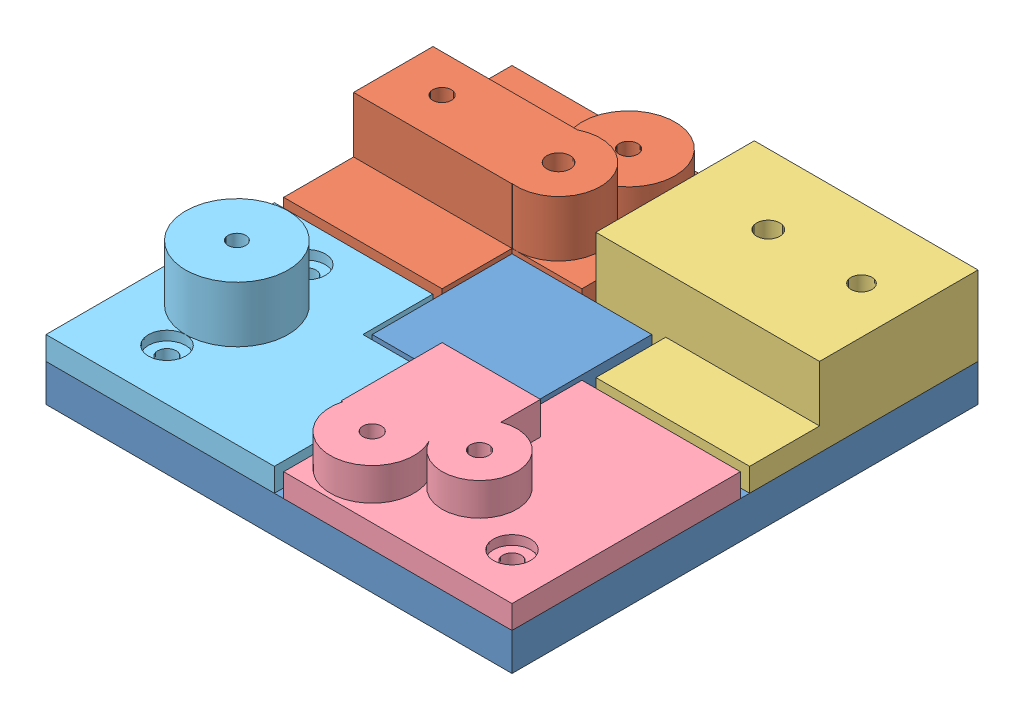
SolidWorks assembly model, configuration Default. Lengths in mm.
Overall size (100 25 100).
5 component instances, 5 part files, 12 mates.
Components (placement in the parent):
- model_1-1: model_1 [Default] at (3.4761 37.87 104.3471) size (100 13 100)
- model_2-1: model_2 [Default] at (3.4761 45.87 53.3471) size (49 17 49)
- model_3-1: model_3 [Default] at (55.4761 45.87 53.3471) size (48 17 49)
- model_4-1: model_4 [Default] at (54.4761 45.87 104.3471) size (49 12 49)
- model_5-1: model_5 [Default] at (3.4761 45.87 104.3471) size (49 17 49)
Mates (geometry in assembly coordinates):
- Coincident1: coincident: plane of model_1-1 through (3.4761 45.87 104.3471) normal (0 1 0); plane of model_2-1 through (3.4761 45.87 53.3471) normal (0 -1 0)
- Coincident2: coincident: plane of model_1-1 through (3.4761 45.87 4.3471) normal (0 0 -1); plane of model_2-1 through (3.4761 50.87 4.3471) normal (0 0 -1)
- Coincident3: coincident aligned: plane of model_1-1 through (3.4761 45.87 104.3471) normal (-1 0 0); plane of model_2-1 through (3.4761 50.87 53.3471) normal (-1 0 0)
- Coincident4: coincident: plane of model_1-1 through (3.4761 45.87 104.3471) normal (0 1 0); plane of model_3-1 through (55.4761 45.87 53.3471) normal (0 -1 0)
- Coincident5: coincident: plane of model_1-1 through (103.4761 45.87 104.3471) normal (1 0 0); plane of model_3-1 through (103.4761 50.87 53.3471) normal (1 0 0)
- Coincident6: coincident aligned: plane of model_1-1 through (3.4761 45.87 4.3471) normal (0 0 -1); plane of model_3-1 through (55.4761 50.87 4.3471) normal (0 0 -1)
- Coincident7: coincident: plane of model_1-1 through (3.4761 45.87 104.3471) normal (0 1 0); plane of model_4-1 through (54.4761 45.87 104.3471) normal (0 -1 0)
- Coincident8: coincident: plane of model_1-1 through (103.4761 45.87 104.3471) normal (1 0 0); plane of model_4-1 through (103.4761 50.87 104.3471) normal (1 0 0)
- Coincident9: coincident aligned: plane of model_1-1 through (3.4761 45.87 104.3471) normal (0 0 1); plane of model_4-1 through (54.4761 50.87 104.3471) normal (0 0 1)
- Coincident10: coincident: plane of model_1-1 through (3.4761 45.87 104.3471) normal (0 1 0); plane of model_5-1 through (3.4761 45.87 104.3471) normal (0 -1 0)
- Coincident11: coincident: plane of model_1-1 through (3.4761 45.87 104.3471) normal (-1 0 0); plane of model_5-1 through (3.4761 50.87 104.3471) normal (-1 0 0)
- Coincident12: coincident aligned: plane of model_1-1 through (3.4761 45.87 104.3471) normal (0 0 1); plane of model_5-1 through (3.4761 50.87 104.3471) normal (0 0 1)
